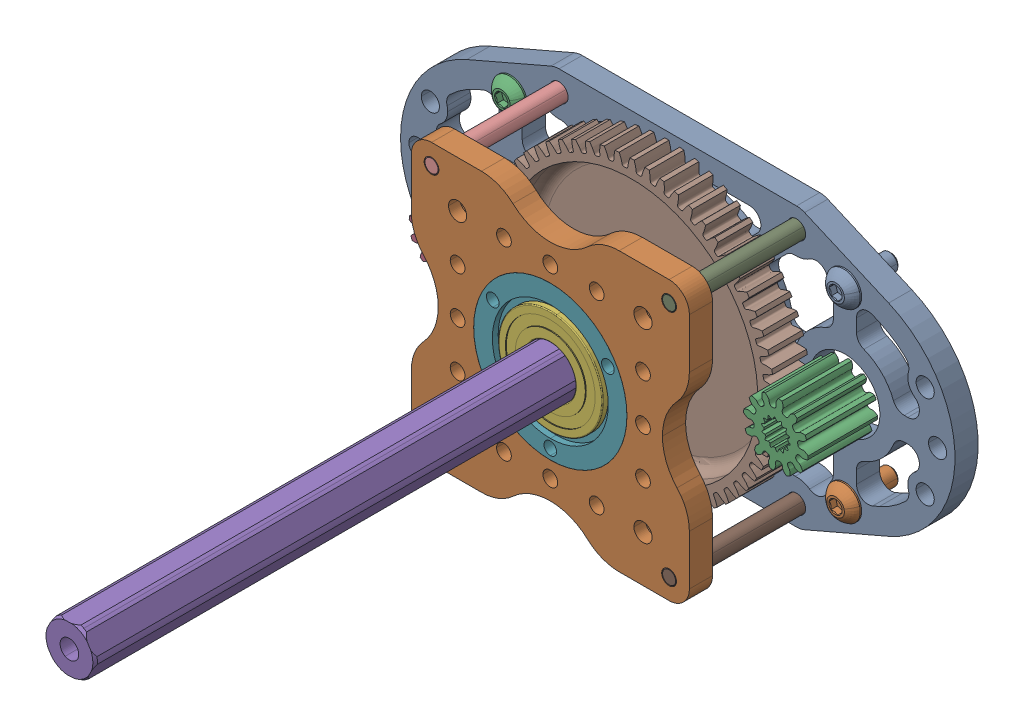
SolidWorks assembly WCP-0557 Rev1 - WCP Single Stage Gearbox_0.5_ Hex.step, configuration Default. Lengths in mm.
Overall size (151.92 82.41 179.39).
26 component instances, 14 part files, 0 mates.
Components (placement in the parent):
- WCP-0557-001 Rev1.step-1: WCP-0557-001 Rev1.step [Default] at origin size (151.92 76.2 6.35)
- WCP-0557-002 Rev1.step-1: WCP-0557-002 Rev1.step [Default] at (0 0 34.925) size (76.2 76.2 6.35)
- 217-6515_Falcon_500_Default_As Machined_.step-1: 217-6515_Falcon_500_Default_As Machined_.step [Default] at (45.7962 0 -29.375) x (0.866025 0.5 0) z (0 0 1) (suppressed, hidden)
- 217-6515_Falcon_500_Default_As Machined_.step-2: 217-6515_Falcon_500_Default_As Machined_.step [Default] at (-45.7962 0 -29.375) x (0.866025 0.5 0) z (0 0 1) (suppressed, hidden)
- 217-6919_Falcon_12T.step-1: 217-6919_Falcon_12T.step [Default] at (45.7962 0 12.5775) x (0.990666 -0.136309 0) z (0 0 1) size (17.78 17.78 19.05)
- 217-6919_Falcon_12T.step-2: 217-6919_Falcon_12T.step [Default] at (-45.7962 0 12.5775) x (0.990666 -0.136309 0) z (0 0 1) size (17.78 17.78 19.05)
- WCP-0226 Rev1.step-1: WCP-0226 Rev1.step [Default] at (32.5438 -32.5438 17.4625) x (0 0 -1) z (0.876265 0.481829 0) (suppressed, hidden)
- WCP-0226 Rev1.step-2: WCP-0226 Rev1.step [Default] at (32.5438 32.5438 17.4625) x (0 0 -1) z (-0.524135 0.851635 0) (suppressed, hidden)
- WCP-0226 Rev1.step-3: WCP-0226 Rev1.step [Default] at (-32.5438 -32.5438 17.4625) x (0 0 -1) z (0.876265 0.481829 0) (suppressed, hidden)
- WCP-0226 Rev1.step-4: WCP-0226 Rev1.step [Default] at (-32.5438 32.5438 17.4625) x (0 0 -1) z (0.876265 0.481829 0) (suppressed, hidden)
- WCP-0557-004 Rev1.step-1: WCP-0557-004 Rev1.step [Default] at (0 0 0.7937) x (1 0 0) z (0 -1 0) size (45 7.94 45)
- WCP-0781_0_500_flanged_bearing.step-1: WCP-0781_0_500_flanged_bearing.step [Default] at (0 0 -3.175) x (0.999832 0.018325 0) z (0.018325 -0.999832 0) size (31.12 7.94 31.12)
- WCP-0557-004 Rev1.step-2: WCP-0557-004 Rev1.step [Default] at (0 0 34.1313) x (1 0 0) z (0 1 0) size (45 7.94 45)
- WCP-0790_500L_500_hex.step-1: WCP-0790_500L_500_hex.step [Default] at (0 0 23.7617) x (0.953738 0.300639 0) z (0 0 1) size (19.5 19.5 12.7)
- 10-32 BHCS - No Thread_WCP-0257 - 1.500.step-1: 10-32 BHCS - No Thread_WCP-0257 - 1.500.step [Default] at (32.5438 32.5438 0) x (0.63562 -0.772002 0) z (0.772002 0.63562 0) size (9.17 40.67 9.17)
- 10-32 BHCS - No Thread_WCP-0257 - 1.500.step-2: 10-32 BHCS - No Thread_WCP-0257 - 1.500.step [Default] at (-32.5438 32.5438 0) x (0.63562 -0.772002 0) z (0.772002 0.63562 0) size (9.17 40.67 9.17)
- 10-32 BHCS - No Thread_WCP-0257 - 1.500.step-3: 10-32 BHCS - No Thread_WCP-0257 - 1.500.step [Default] at (32.5438 -32.5438 0) x (0.63562 -0.772002 0) z (0.772002 0.63562 0) size (9.17 40.67 9.17)
- 10-32 BHCS - No Thread_WCP-0257 - 1.500.step-4: 10-32 BHCS - No Thread_WCP-0257 - 1.500.step [Default] at (-32.5438 -32.5438 0) x (0.63562 -0.772002 0) z (0.772002 0.63562 0) size (9.17 40.67 9.17)
- 10-32 BHCS - No Thread_WCP-0253 - 0.500.step-1: 10-32 BHCS - No Thread_WCP-0253 - 0.500.step [Default] at (45.7962 25.4 3.175) x (0.313732 -0.949511 0) z (-0.949511 -0.313732 0) size (9.17 15.27 9.17)
- 10-32 BHCS - No Thread_WCP-0253 - 0.500.step-2: 10-32 BHCS - No Thread_WCP-0253 - 0.500.step [Default] at (45.7962 -25.4 3.175) x (0.270491 -0.962723 0) z (-0.962723 -0.270491 0) size (9.17 15.27 9.17)
- 10-32 BHCS - No Thread_WCP-0253 - 0.500.step-3: 10-32 BHCS - No Thread_WCP-0253 - 0.500.step [Default] at (-45.7962 25.4 3.175) x (0.363225 -0.931702 0) z (-0.931702 -0.363225 0) size (9.17 15.27 9.17)
- 10-32 BHCS - No Thread_WCP-0253 - 0.500.step-4: 10-32 BHCS - No Thread_WCP-0253 - 0.500.step [Default] at (-45.7962 -25.4 3.175) x (0.510832 -0.85968 0) z (-0.85968 -0.510832 0) size (9.17 15.27 9.17)
- WCP-0832 Rev1.step-1: WCP-0832 Rev1.step [Default] at (0 0 87.3125) x (0.457904 0.889002 0) z (0 0 1) size (13.75 13.61 175.64)
- WCP-0785_0_500_flanged_thunderhex_bearing.step-1: WCP-0785_0_500_flanged_thunderhex_bearing.step [Default] at (0 0 34.1313) x (-0.110978 -0.993823 0) z (0 0 -1) size (31.12 31.12 7.94)
- WCP-0229 Rev1.step-1: WCP-0229 Rev1.step [Default] at (0 0 -3.6195) x (0 0 1) z (-0.791548 -0.611107 0) size (0.89 16.1 14.34)
- WCP-0187 Rev1.step-1: WCP-0187 Rev1.step [Default] at (0 0 11.0871) x (0.99882 0.048566 0) z (0 0 1) size (78.68 78.68 12.65)
